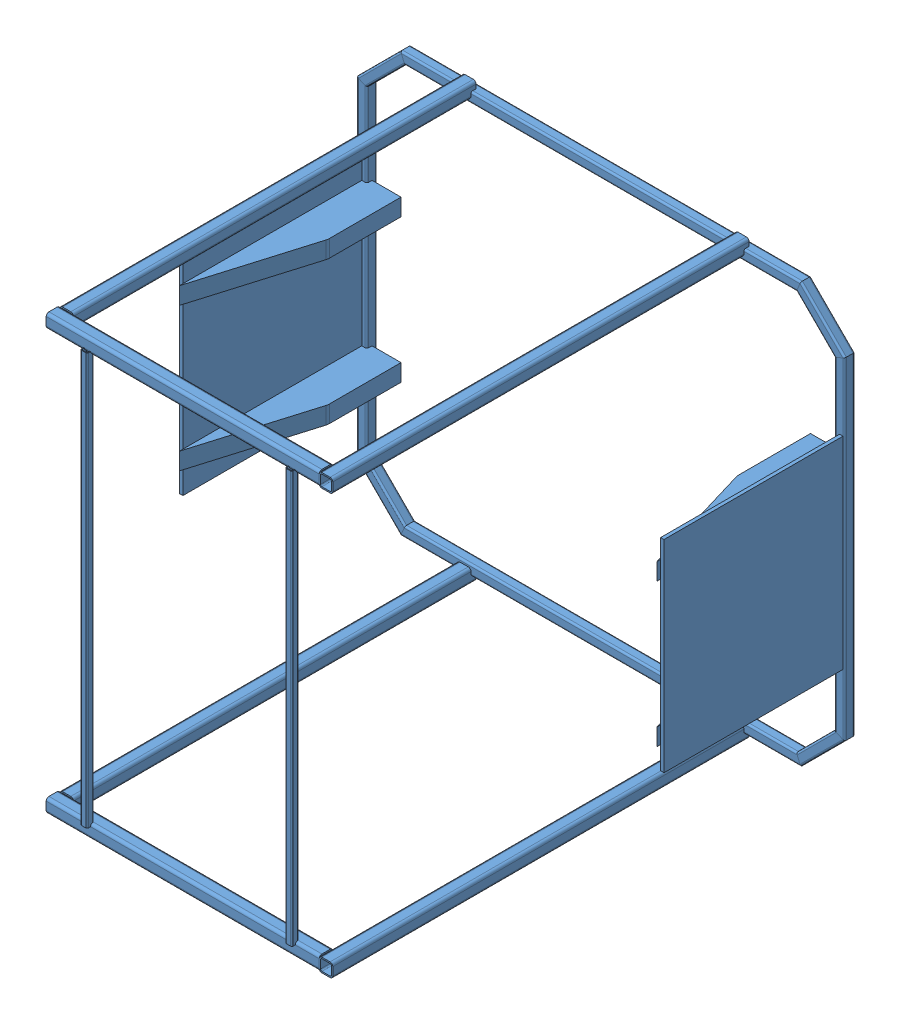
SolidWorks assembly maszyna, configuration Domyślna. Lengths in mm.
Overall size (1430 1270 1245).
5 component instances, 2 part files, 8 mates.
Components (placement in the parent):
- rama-1: rama [Domyślna<Obrobiona>] at (-82.7026 94.6486 1752.9266) size (1430 1270 1245)
- pila-1: pila [Domyślna] at (-534.8691 552.7933 1823.603) x (0.707107 0.707107 0) z (-0.707107 0.707107 0) size (508.56 311.6 431.24) (hidden)
- pila-2: pila [Domyślna] at (455.7781 466.479 1823.603) x (0.707107 -0.707107 0) z (0.707107 0.707107 0) size (508.56 311.6 431.24) (hidden)
- pila-3: pila [Domyślna] at (-621.7101 -276.6551 1823.603) x (-0.707107 0.707107 0) z (-0.707107 -0.707107 0) size (508.56 311.6 431.24) (hidden)
- pila-4: pila [Domyślna] at (370.0193 -362.9407 1823.603) x (-0.707107 -0.707107 0) z (0.707107 -0.707107 0) size (508.56 311.6 431.24) (hidden)
Mates (geometry in assembly coordinates):
- Wspólnie11: coincident anti-aligned: plane of rama-1 through (497.2974 684.8486 1767.9266) normal (0 0 1); plane of pila-1 through (-832.6039 555.2642 1767.9266) normal (0 0 -1)
- Wspólnie12: coincident: plane of pila-1 through (-612.6937 544.6576 1815.1891) normal (0.707107 -0.707107 0)
- Wspólnie14: coincident: plane of pila-2 through (447.6424 544.3036 1815.1891) normal (-0.707107 -0.707107 0)
- Wspólnie15: coincident: plane of pila-3 through (-613.5743 -354.4797 1815.1891) normal (0.707107 0.707107 0)
- Wspólnie16: coincident: plane of pila-4 through (447.8439 -354.8049 1815.1891) normal (-0.707107 0.707107 0)
- Wspólnie17: coincident anti-aligned: plane of rama-1 through (610.3677 567.7189 1767.9266) normal (0 0 1); plane of pila-2 through (458.249 764.2138 1767.9266) normal (0 0 -1)
- Wspólnie18: coincident anti-aligned: plane of rama-1 through (490.3677 -498.4218 1767.9266) normal (0 0 1); plane of pila-4 through (667.7541 -365.4115 1767.9266) normal (0 0 -1)
- Wspólnie19: coincident anti-aligned: plane of rama-1 through (-775.773 -378.4218 1767.9266) normal (0 0 1); plane of pila-3 through (-624.1809 -574.39 1767.9266) normal (0 0 -1)
